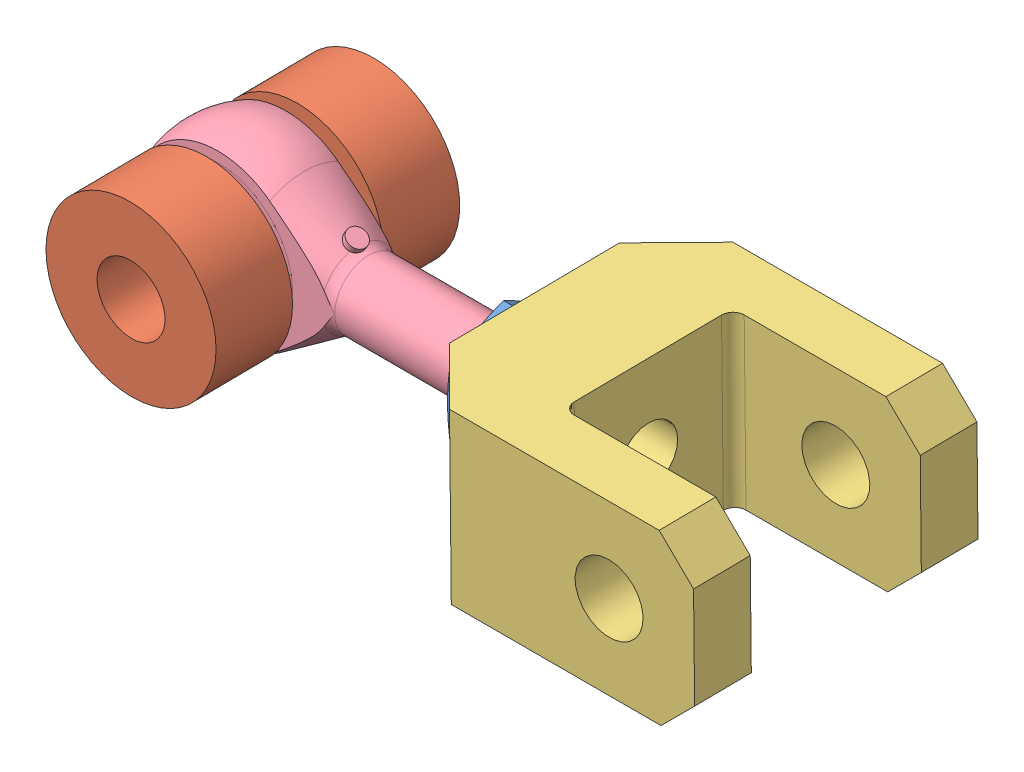
SolidWorks assembly Assemblage1, configuration Défaut. Lengths in mm.
Overall size (123.17 40.78 50.31).
5 component instances, 4 part files, 8 mates.
Components (placement in the parent):
- ecrou bas M12-1: ecrou bas M12 [Défaut] at (-27.7907 4.0327 21.9393) size (6 21.94 19)
- entretoise-1: entretoise [Défaut] at (-71.6429 4.2602 0.4405) x (0.474574 0.880166 0.009311) z (0 -0.010578 0.999944) size (30 30 13.5)
- fourchette v2-1: fourchette v2 [Défaut] at (-1.7907 4.0327 21.9393) x (0 -0.010578 0.999944) z (0 0.999944 0.010578) size (50 53 30)
- Rotule M12dr-1: Rotule M12dr [Défaut] at (-17.6429 4.0327 21.9393) x (-1 0 0) z (0 0.010578 -0.999944) size (70 32 32)
- entretoise-2: entretoise [Défaut] at (-71.6429 3.9481 29.9389) x (1 0 0) z (0 -0.010578 0.999944) size (30 30 13.5)
Mates (geometry in assembly coordinates):
- Coaxiale1: concentric aligned: cylinder of fourchette v2-1 through (-21.7907 4.0327 21.9393) axis (-1 0 0) radius 5.1; cylinder of Rotule M12dr-1 through (-34.3881 4.0327 21.9393) axis (-1 0 0) radius 6
- Parallèle1: parallel anti-aligned: plane of fourchette v2-1 through (31.2093 -11.2309 46.7792) normal (0 -0.010578 0.999944); plane of Rotule M12dr-1 through (-71.0705 -2.7323 13.8673) normal (0 0.010578 -0.999944)
- Coaxiale2: concentric anti-aligned: cylinder of ecrou bas M12-1 through (-24.7907 4.0327 21.9393) axis (1 0 0) radius 5.053; cylinder of Rotule M12dr-1 through (-34.3881 4.0327 21.9393) axis (-1 0 0) radius 6
- Coïncidente2: coincident anti-aligned: plane of ecrou bas M12-1 through (-21.7907 11.7827 21.9393) normal (1 0 0); plane of fourchette v2-1 through (-21.7907 -10.8078 6.7815) normal (-1 0 0)
- Coaxiale3: concentric: cylinder of entretoise-1 through (-71.6429 4.2904 -2.421) axis (0 0.010578 -0.999944) radius 6; cylinder of Rotule M12dr-1 through (-71.6429 4.0772 17.7395) axis (0 0.010578 -0.999944) radius 6
- Coaxiale4: concentric: cylinder of Rotule M12dr-1 through (-71.6429 4.0772 17.7395) axis (0 0.010578 -0.999944) radius 6; cylinder of entretoise-2 through (-71.6429 3.4369 78.2657) axis (0 0.010578 -0.999944) radius 6
- Coïncidente3: coincident anti-aligned: plane of entretoise-1 through (-71.6429 4.1174 13.9398) normal (0 -0.010578 0.999944); plane of Rotule M12dr-1 through (-71.6429 -2.7323 13.8673) normal (0 0.010578 -0.999944)
- Coïncidente4: coincident anti-aligned: plane of Rotule M12dr-1 through (-71.6429 -2.9015 29.8664) normal (0 -0.010578 0.999944); plane of entretoise-2 through (-71.6429 3.9481 29.9389) normal (0 0.010578 -0.999944)
